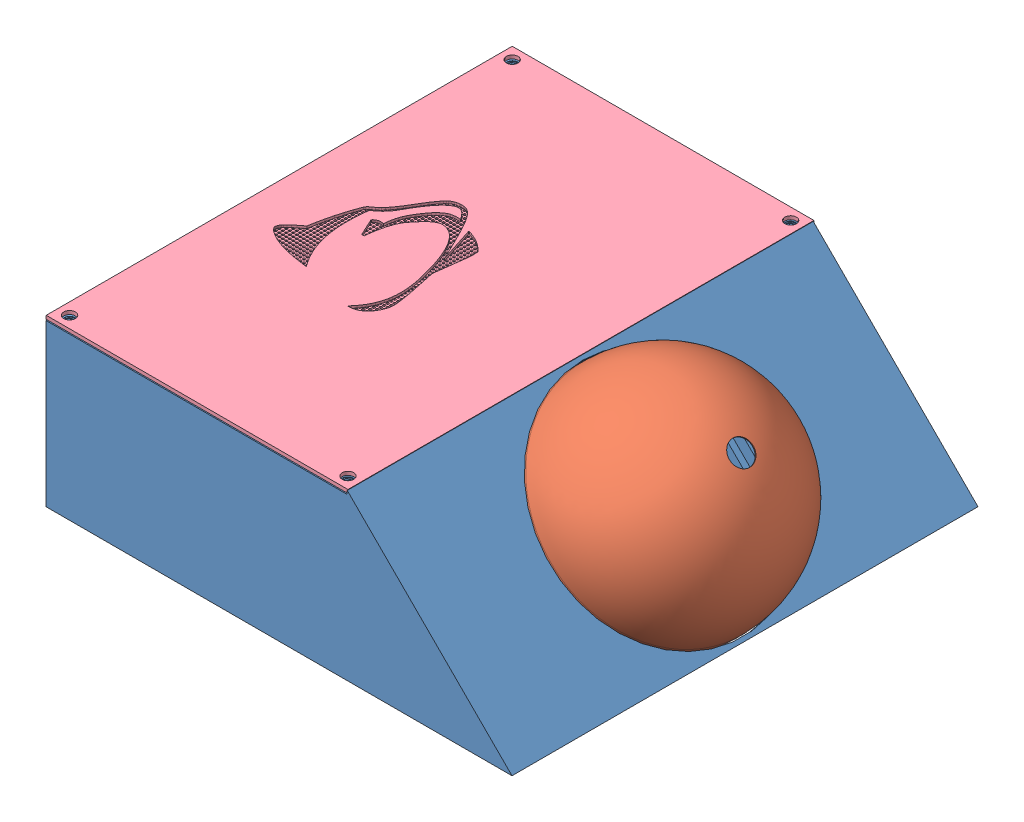
SolidWorks assembly Assem1, configuration Default. Lengths in mm.
Overall size (118.09 53.42 101.75).
4 component instances, 4 part files, 4 mates.
Components (placement in the parent):
- RpiHousingUpdated-1: RpiHousingUpdated [Default] at (7.2335 65.9352 85.4079) size (101.6 35.92 101.6)
- CAP-1: CAP [Default] at (90.8352 83.9335 136.1544) x (0.707107 -0.707107 0) z (0 0 1) size (48.77 26.78 48.77)
- Divider-1: Divider [Default] at (52.4978 84.5842 136.3349) x (0 0 -1) z (0.000761 -1 0) size (98.81 0.46 33.02)
- RpiRoof-2: RpiRoof [Default] at (40.0195 101.189 136.0529) x (0 0 -1) z (1 0 0) size (101.6 0.76 65.79)
Mates (geometry in assembly coordinates):
- Coincident1: coincident anti-aligned: plane of RpiHousingUpdated-1 through (89.0769 82.0996 136.2079) normal (0.707107 0.707107 0); plane of CAP-1 through (89.0391 82.1374 136.1544) normal (-0.707107 -0.707107 0)
- Coincident3: coincident anti-aligned: plane of RpiHousingUpdated-1 through (7.2335 68.0742 85.4079) normal (0 1 0); line of Divider-1 through (52.5104 68.0742 185.7379) axis (0 0 -1)
- Coincident4: coincident anti-aligned: plane of RpiHousingUpdated-1 through (52.9535 68.0742 185.7379) normal (0 0 -1); plane of Divider-1 through (52.9424 101.0945 185.7379) normal (0 0 1)
- Coincident8: coincident anti-aligned: plane of RpiHousingUpdated-1 through (72.9125 101.0942 85.4079) normal (-1 0 0); plane of RpiRoof-2 through (72.9125 101.951 186.8529) normal (1 0 0)
